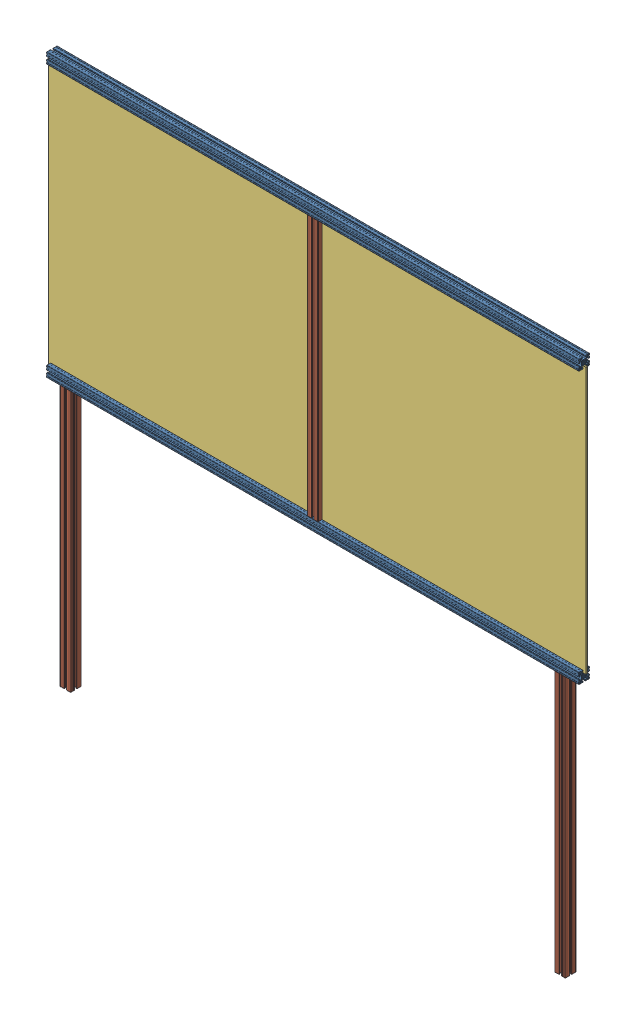
SolidWorks assembly Lateral_S_Porta_Mod2, configuration Valor predeterminado. Lengths in mm.
Overall size (2020 2040 40).
7 component instances, 3 part files, 9 mates.
Components (placement in the parent):
- Perfil_Alum_4x4x200-1: Perfil_Alum_4x4x200 [Valor predeterminado] at (40.4856 -17.0967 -270.6056) x (0 0 -1) z (1 0 0) size (40 40 2000)
- Perfil_Alum_4x4x200-2: Perfil_Alum_4x4x200 [Valor predeterminado] at (40.4856 1002.9033 -270.6056) x (0 0 -1) z (1 0 0) size (40 40 2000)
- Perfil_Alum_4x4x98-1: Perfil_Alum_4x4x98 [Valor predeterminado] at (40.4856 492.9033 -270.6056) x (1 0 0) z (0 -1 0) size (40 40 980)
- Policarbonato 1x1-1: Policarbonato 1x1 [Valor predeterminado] at (550.4856 492.9033 -270.6056) size (1000 1000 6)
- Policarbonato 1x1-2: Policarbonato 1x1 [Valor predeterminado] at (-469.5144 492.9033 -270.6056) size (1000 1000 6)
- Perfil_Alum_4x4x98-2: Perfil_Alum_4x4x98 [Valor predeterminado] at (-889.5144 -527.0967 -270.6056) x (1 0 0) z (0 -1 0) size (40 40 980)
- Perfil_Alum_4x4x98-3: Perfil_Alum_4x4x98 [Valor predeterminado] at (970.4856 -527.0967 -270.6056) x (1 0 0) z (0 -1 0) size (40 40 980)
Mates (geometry in assembly coordinates):
- Distância6: distance = 980 mm: line of Perfil_Alum_4x4x200-1 through (1040.4856 2.9033 -256.2056) axis (0 0 1); line of Perfil_Alum_4x4x98-1 through (60.4856 2.9033 -256.2056) axis (0 0 1)
- Coincidente16: coincident anti-aligned: plane of Perfil_Alum_4x4x98-1 through (30.4856 2.9033 -275.7061) normal (-1 0 0); plane of Policarbonato 1x1-2 through (30.4856 992.9033 -267.6056) normal (1 0 0)
- Coincidente17: coincident anti-aligned: plane of Perfil_Alum_4x4x200-1 through (1040.4856 -7.0967 -265.5051) normal (0 1 0); plane of Policarbonato 1x1-2 through (-969.5144 -7.0967 -267.6056) normal (0 -1 0)
- Distância7: distance = 1.15 mm anti-aligned: plane of Perfil_Alum_4x4x200-2 through (1040.4856 987.0033 -266.4556) normal (0 0 -1); plane of Policarbonato 1x1-2 through (-469.5144 492.9033 -267.6056) normal (0 0 1)
- Coincidente19: coincident anti-aligned: plane of Perfil_Alum_4x4x200-1 through (1040.4856 -7.0967 -265.5051) normal (0 1 0); plane of Policarbonato 1x1-1 through (50.4856 -7.0967 -267.6056) normal (0 -1 0)
- Coincidente20: coincident anti-aligned: plane of Perfil_Alum_4x4x98-1 through (50.4856 2.9033 -265.5051) normal (1 0 0); plane of Policarbonato 1x1-1 through (50.4856 992.9033 -267.6056) normal (-1 0 0)
- Distância8: distance = 1.15 mm anti-aligned: plane of Perfil_Alum_4x4x200-2 through (1040.4856 987.0033 -266.4556) normal (0 0 -1); plane of Policarbonato 1x1-1 through (550.4856 492.9033 -267.6056) normal (0 0 1)
- Distância9: distance = 50 mm: line of Perfil_Alum_4x4x200-1 through (1040.4856 -37.0967 -285.0056) axis (0 0 -1); line of Perfil_Alum_4x4x98-3 through (990.4856 -37.0967 -289.1056) axis (0 0 1)
- Distância10: distance = 50 mm: line of Perfil_Alum_4x4x98-2 through (-909.5144 -37.0967 -285.0056) axis (0 0 -1); line of Perfil_Alum_4x4x200-1 through (-959.5144 -37.0967 -285.0056) axis (0 0 -1)
